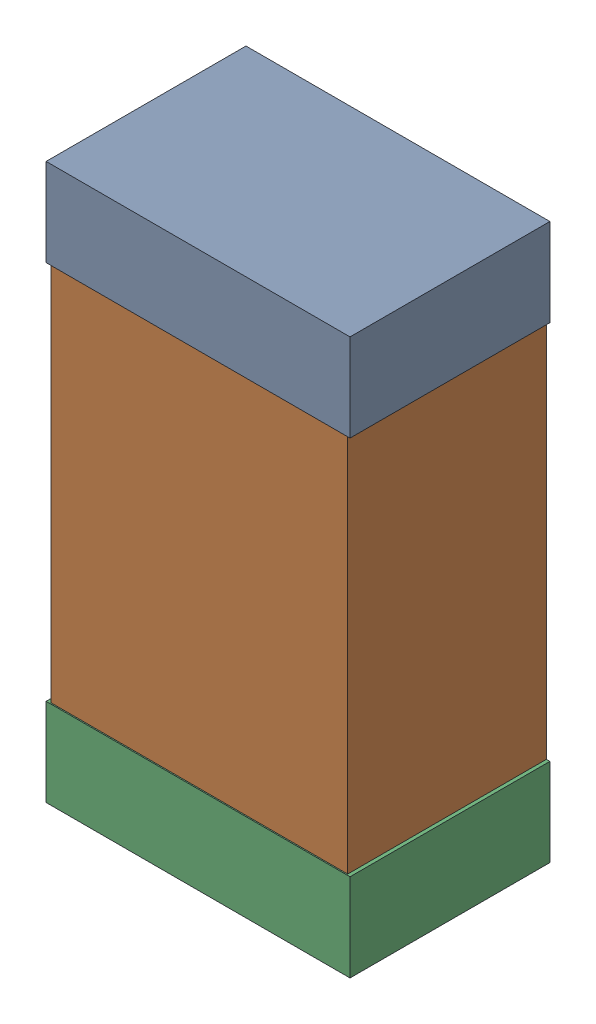
SolidWorks assembly R3_Motor_6Kanaloa_v2.0.0_Loko, configuration Default. Lengths in mm.
Overall size (1.3 2.38 0.85).
6 component instances, 2 part files, 0 mates.
Components (placement in the parent):
- 330415056_1-1: 330415056_1 [Default] at (72.8083 75.9218 0) size (1.3 0.38 0.85)
  - Extruded_29-1: Extruded_29 [Default] at origin size (1.3 0.38 0.85)
- 334787376_1-1: 334787376_1 [Default] at (72.8083 74.9218 0) size (1.27 2.2 0.85)
  - Extruded_30-1: Extruded_30 [Default] at origin size (1.27 2.2 0.85)
- 330415056_1-2: 330415056_1 [Default] at (72.8083 73.9218 0) size (1.3 0.38 0.85)
  - Extruded_29-1: Extruded_29 [Default] at origin size (1.3 0.38 0.85)
